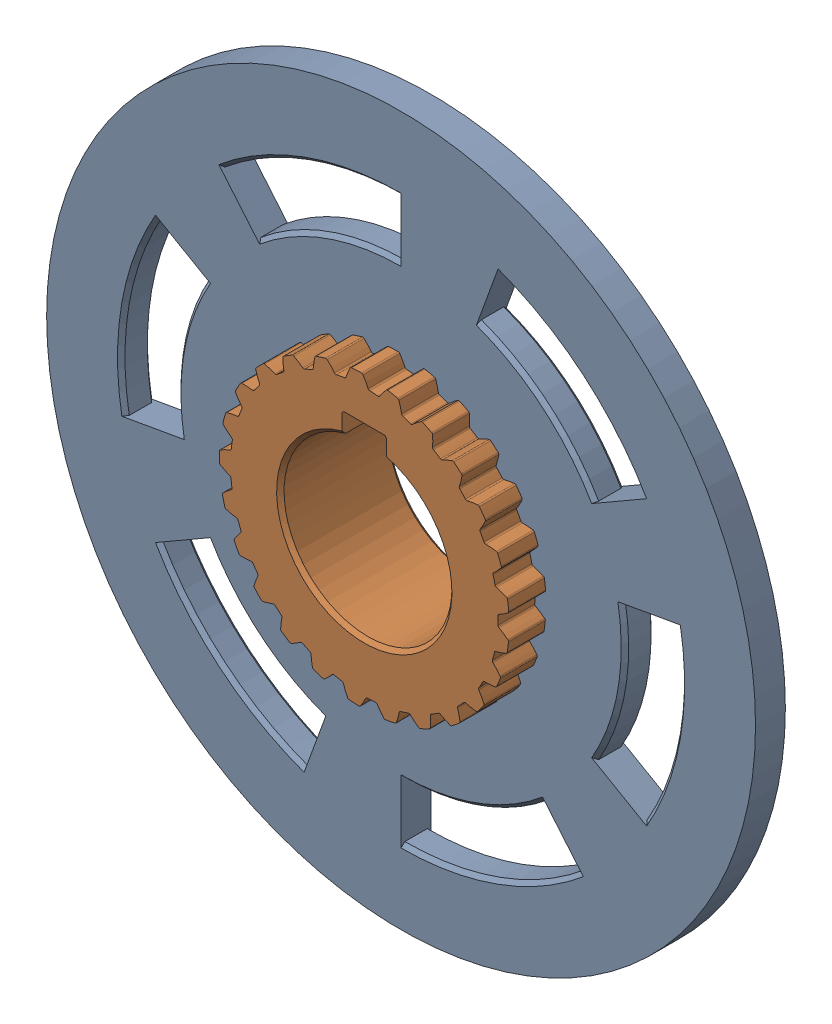
SolidWorks assembly Dog_Mechanism_2_&_3, configuration Default. Lengths in mm.
Overall size (190 190 30).
2 component instances, 2 part files, 1 mates.
Components (placement in the parent):
- Dog_Ring_2_&_3-1: Dog_Ring_2_&_3 [Default] at (3.7584 2.3913 -5.787) size (190 190 8)
- Dog_Ring_Sleeve_gear_2_3-1: Dog_Ring_Sleeve_gear_2_3 [Default] at (3.7584 2.3913 -17.9224) size (77.57 77.67 30)
Mates (geometry in assembly coordinates):
- Concentric1: concentric aligned: cylinder of Dog_Ring_2_&_3-1 through (3.7584 2.3913 2.213) axis (0 0 -1) radius 95; cylinder of Dog_Ring_Sleeve_gear_2_3-1 through (3.7584 2.3913 12.0776) axis (0 0 -1) radius 38.85
